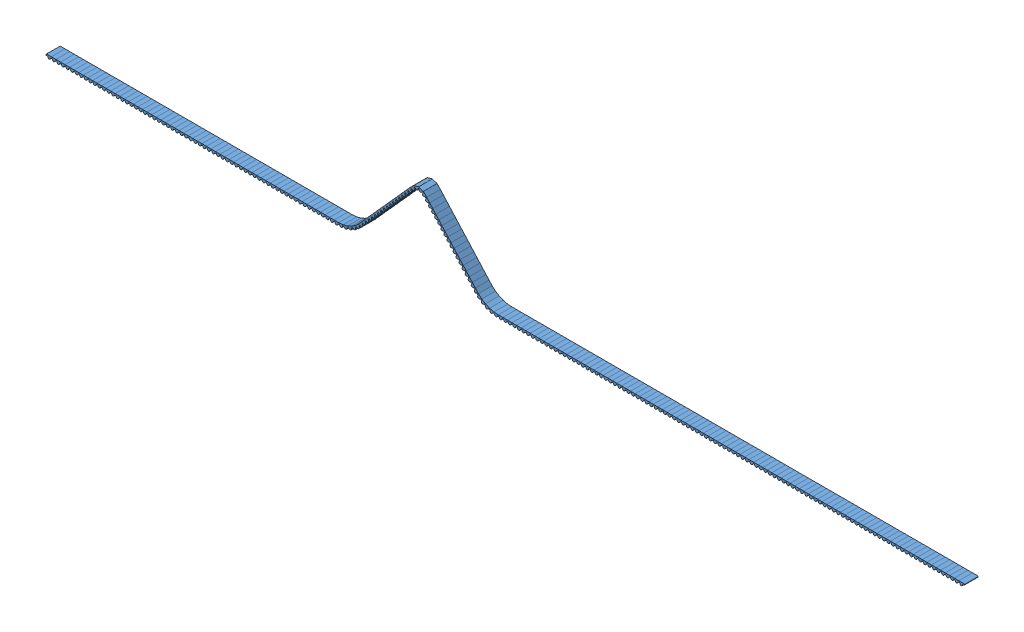
SolidWorks assembly TimingBelt2, configuration Timing Belt 430mm. Lengths in mm.
Overall size (824.67 32.64 6.23).
215 component instances, 2 part files, 2 mates.
Components (placement in the parent):
- Path^TimingBelt2-1: Path^TimingBelt2 [По умолчанию] at (723.3973 0 0) size (824.67 31.3 0) (virtual)
- PartOfBeltP2W6^TimingBelt2-1: PartOfBeltP2W6^TimingBelt2 [По умолчанию] at (982.9414 0 6) x (-1 0 0) z (0 0 -1) size (2.75 1.38 6.23) (virtual)
- PartOfBeltP2W6^TimingBelt2-485: PartOfBeltP2W6^TimingBelt2 [По умолчанию] at (980.9414 0 6) x (-1 0 0) z (0 0 -1) size (2.75 1.38 6.23) (virtual)
- PartOfBeltP2W6^TimingBelt2-486: PartOfBeltP2W6^TimingBelt2 [По умолчанию] at (978.9414 0 6) x (-1 0 0) z (0 0 -1) size (2.75 1.38 6.23) (virtual)
- PartOfBeltP2W6^TimingBelt2-487: PartOfBeltP2W6^TimingBelt2 [По умолчанию] at (976.9414 0 6) x (-1 0 0) z (0 0 -1) size (2.75 1.38 6.23) (virtual)
- PartOfBeltP2W6^TimingBelt2-488: PartOfBeltP2W6^TimingBelt2 [По умолчанию] at (974.9414 0 6) x (-1 0 0) z (0 0 -1) size (2.75 1.38 6.23) (virtual)
- PartOfBeltP2W6^TimingBelt2-489: PartOfBeltP2W6^TimingBelt2 [По умолчанию] at (972.9414 0 6) x (-1 0 0) z (0 0 -1) size (2.75 1.38 6.23) (virtual)
- PartOfBeltP2W6^TimingBelt2-490: PartOfBeltP2W6^TimingBelt2 [По умолчанию] at (970.9414 0 6) x (-1 0 0) z (0 0 -1) size (2.75 1.38 6.23) (virtual)
- PartOfBeltP2W6^TimingBelt2-491: PartOfBeltP2W6^TimingBelt2 [По умолчанию] at (968.9414 0 6) x (-1 0 0) z (0 0 -1) size (2.75 1.38 6.23) (virtual)
- PartOfBeltP2W6^TimingBelt2-492: PartOfBeltP2W6^TimingBelt2 [По умолчанию] at (966.9414 0 6) x (-1 0 0) z (0 0 -1) size (2.75 1.38 6.23) (virtual)
- PartOfBeltP2W6^TimingBelt2-493: PartOfBeltP2W6^TimingBelt2 [По умолчанию] at (964.9414 0 6) x (-1 0 0) z (0 0 -1) size (2.75 1.38 6.23) (virtual)
- PartOfBeltP2W6^TimingBelt2-494: PartOfBeltP2W6^TimingBelt2 [По умолчанию] at (962.9414 0 6) x (-1 0 0) z (0 0 -1) size (2.75 1.38 6.23) (virtual)
- PartOfBeltP2W6^TimingBelt2-495: PartOfBeltP2W6^TimingBelt2 [По умолчанию] at (960.9414 0 6) x (-1 0 0) z (0 0 -1) size (2.75 1.38 6.23) (virtual)
- PartOfBeltP2W6^TimingBelt2-496: PartOfBeltP2W6^TimingBelt2 [По умолчанию] at (958.9414 0 6) x (-1 0 0) z (0 0 -1) size (2.75 1.38 6.23) (virtual)
- PartOfBeltP2W6^TimingBelt2-497: PartOfBeltP2W6^TimingBelt2 [По умолчанию] at (956.9414 0 6) x (-1 0 0) z (0 0 -1) size (2.75 1.38 6.23) (virtual)
- PartOfBeltP2W6^TimingBelt2-498: PartOfBeltP2W6^TimingBelt2 [По умолчанию] at (954.9414 0 6) x (-1 0 0) z (0 0 -1) size (2.75 1.38 6.23) (virtual)
- PartOfBeltP2W6^TimingBelt2-499: PartOfBeltP2W6^TimingBelt2 [По умолчанию] at (952.9414 0 6) x (-1 0 0) z (0 0 -1) size (2.75 1.38 6.23) (virtual)
- PartOfBeltP2W6^TimingBelt2-500: PartOfBeltP2W6^TimingBelt2 [По умолчанию] at (950.9414 0 6) x (-1 0 0) z (0 0 -1) size (2.75 1.38 6.23) (virtual)
- PartOfBeltP2W6^TimingBelt2-501: PartOfBeltP2W6^TimingBelt2 [По умолчанию] at (948.9414 0 6) x (-1 0 0) z (0 0 -1) size (2.75 1.38 6.23) (virtual)
- PartOfBeltP2W6^TimingBelt2-502: PartOfBeltP2W6^TimingBelt2 [По умолчанию] at (946.9414 0 6) x (-1 0 0) z (0 0 -1) size (2.75 1.38 6.23) (virtual)
- PartOfBeltP2W6^TimingBelt2-503: PartOfBeltP2W6^TimingBelt2 [По умолчанию] at (944.9414 0 6) x (-1 0 0) z (0 0 -1) size (2.75 1.38 6.23) (virtual)
- PartOfBeltP2W6^TimingBelt2-504: PartOfBeltP2W6^TimingBelt2 [По умолчанию] at (942.9414 0 6) x (-1 0 0) z (0 0 -1) size (2.75 1.38 6.23) (virtual)
- PartOfBeltP2W6^TimingBelt2-505: PartOfBeltP2W6^TimingBelt2 [По умолчанию] at (940.9414 0 6) x (-1 0 0) z (0 0 -1) size (2.75 1.38 6.23) (virtual)
- PartOfBeltP2W6^TimingBelt2-506: PartOfBeltP2W6^TimingBelt2 [По умолчанию] at (938.9414 0 6) x (-1 0 0) z (0 0 -1) size (2.75 1.38 6.23) (virtual)
- PartOfBeltP2W6^TimingBelt2-507: PartOfBeltP2W6^TimingBelt2 [По умолчанию] at (936.9414 0 6) x (-1 0 0) z (0 0 -1) size (2.75 1.38 6.23) (virtual)
- PartOfBeltP2W6^TimingBelt2-508: PartOfBeltP2W6^TimingBelt2 [По умолчанию] at (934.9414 0 6) x (-1 0 0) z (0 0 -1) size (2.75 1.38 6.23) (virtual)
- PartOfBeltP2W6^TimingBelt2-509: PartOfBeltP2W6^TimingBelt2 [По умолчанию] at (932.9414 0 6) x (-1 0 0) z (0 0 -1) size (2.75 1.38 6.23) (virtual)
- PartOfBeltP2W6^TimingBelt2-510: PartOfBeltP2W6^TimingBelt2 [По умолчанию] at (930.9414 0 6) x (-1 0 0) z (0 0 -1) size (2.75 1.38 6.23) (virtual)
- PartOfBeltP2W6^TimingBelt2-511: PartOfBeltP2W6^TimingBelt2 [По умолчанию] at (928.9414 0 6) x (-1 0 0) z (0 0 -1) size (2.75 1.38 6.23) (virtual)
- PartOfBeltP2W6^TimingBelt2-512: PartOfBeltP2W6^TimingBelt2 [По умолчанию] at (926.9414 0 6) x (-1 0 0) z (0 0 -1) size (2.75 1.38 6.23) (virtual)
- PartOfBeltP2W6^TimingBelt2-513: PartOfBeltP2W6^TimingBelt2 [По умолчанию] at (924.9414 0 6) x (-1 0 0) z (0 0 -1) size (2.75 1.38 6.23) (virtual)
- PartOfBeltP2W6^TimingBelt2-514: PartOfBeltP2W6^TimingBelt2 [По умолчанию] at (922.9414 0 6) x (-1 0 0) z (0 0 -1) size (2.75 1.38 6.23) (virtual)
- PartOfBeltP2W6^TimingBelt2-515: PartOfBeltP2W6^TimingBelt2 [По умолчанию] at (920.9414 0 6) x (-1 0 0) z (0 0 -1) size (2.75 1.38 6.23) (virtual)
- PartOfBeltP2W6^TimingBelt2-516: PartOfBeltP2W6^TimingBelt2 [По умолчанию] at (918.9414 0 6) x (-1 0 0) z (0 0 -1) size (2.75 1.38 6.23) (virtual)
- PartOfBeltP2W6^TimingBelt2-517: PartOfBeltP2W6^TimingBelt2 [По умолчанию] at (916.9414 0 6) x (-1 0 0) z (0 0 -1) size (2.75 1.38 6.23) (virtual)
- PartOfBeltP2W6^TimingBelt2-518: PartOfBeltP2W6^TimingBelt2 [По умолчанию] at (914.9414 0 6) x (-1 0 0) z (0 0 -1) size (2.75 1.38 6.23) (virtual)
- PartOfBeltP2W6^TimingBelt2-519: PartOfBeltP2W6^TimingBelt2 [По умолчанию] at (912.9414 0 6) x (-1 0 0) z (0 0 -1) size (2.75 1.38 6.23) (virtual)
- PartOfBeltP2W6^TimingBelt2-520: PartOfBeltP2W6^TimingBelt2 [По умолчанию] at (910.9414 0 6) x (-1 0 0) z (0 0 -1) size (2.75 1.38 6.23) (virtual)
- PartOfBeltP2W6^TimingBelt2-521: PartOfBeltP2W6^TimingBelt2 [По умолчанию] at (908.9414 0 6) x (-1 0 0) z (0 0 -1) size (2.75 1.38 6.23) (virtual)
- PartOfBeltP2W6^TimingBelt2-522: PartOfBeltP2W6^TimingBelt2 [По умолчанию] at (906.9414 0 6) x (-1 0 0) z (0 0 -1) size (2.75 1.38 6.23) (virtual)
- PartOfBeltP2W6^TimingBelt2-523: PartOfBeltP2W6^TimingBelt2 [По умолчанию] at (904.9414 0 6) x (-1 0 0) z (0 0 -1) size (2.75 1.38 6.23) (virtual)
- PartOfBeltP2W6^TimingBelt2-524: PartOfBeltP2W6^TimingBelt2 [По умолчанию] at (902.9414 0 6) x (-1 0 0) z (0 0 -1) size (2.75 1.38 6.23) (virtual)
- PartOfBeltP2W6^TimingBelt2-525: PartOfBeltP2W6^TimingBelt2 [По умолчанию] at (900.9414 0 6) x (-1 0 0) z (0 0 -1) size (2.75 1.38 6.23) (virtual)
- PartOfBeltP2W6^TimingBelt2-526: PartOfBeltP2W6^TimingBelt2 [По умолчанию] at (898.9414 0 6) x (-1 0 0) z (0 0 -1) size (2.75 1.38 6.23) (virtual)
- PartOfBeltP2W6^TimingBelt2-527: PartOfBeltP2W6^TimingBelt2 [По умолчанию] at (896.9414 0 6) x (-1 0 0) z (0 0 -1) size (2.75 1.38 6.23) (virtual)
- PartOfBeltP2W6^TimingBelt2-528: PartOfBeltP2W6^TimingBelt2 [По умолчанию] at (894.9414 0 6) x (-1 0 0) z (0 0 -1) size (2.75 1.38 6.23) (virtual)
- PartOfBeltP2W6^TimingBelt2-529: PartOfBeltP2W6^TimingBelt2 [По умолчанию] at (892.9414 0 6) x (-1 0 0) z (0 0 -1) size (2.75 1.38 6.23) (virtual)
- PartOfBeltP2W6^TimingBelt2-530: PartOfBeltP2W6^TimingBelt2 [По умолчанию] at (890.9414 0 6) x (-1 0 0) z (0 0 -1) size (2.75 1.38 6.23) (virtual)
- PartOfBeltP2W6^TimingBelt2-531: PartOfBeltP2W6^TimingBelt2 [По умолчанию] at (888.9414 0 6) x (-1 0 0) z (0 0 -1) size (2.75 1.38 6.23) (virtual)
- PartOfBeltP2W6^TimingBelt2-532: PartOfBeltP2W6^TimingBelt2 [По умолчанию] at (886.9414 0 6) x (-1 0 0) z (0 0 -1) size (2.75 1.38 6.23) (virtual)
- PartOfBeltP2W6^TimingBelt2-533: PartOfBeltP2W6^TimingBelt2 [По умолчанию] at (884.9414 0 6) x (-1 0 0) z (0 0 -1) size (2.75 1.38 6.23) (virtual)
- PartOfBeltP2W6^TimingBelt2-534: PartOfBeltP2W6^TimingBelt2 [По умолчанию] at (882.9414 0 6) x (-1 0 0) z (0 0 -1) size (2.75 1.38 6.23) (virtual)
- PartOfBeltP2W6^TimingBelt2-535: PartOfBeltP2W6^TimingBelt2 [По умолчанию] at (880.9414 0 6) x (-1 0 0) z (0 0 -1) size (2.75 1.38 6.23) (virtual)
- PartOfBeltP2W6^TimingBelt2-536: PartOfBeltP2W6^TimingBelt2 [По умолчанию] at (878.9414 0 6) x (-1 0 0) z (0 0 -1) size (2.75 1.38 6.23) (virtual)
- PartOfBeltP2W6^TimingBelt2-537: PartOfBeltP2W6^TimingBelt2 [По умолчанию] at (876.9414 0 6) x (-1 0 0) z (0 0 -1) size (2.75 1.38 6.23) (virtual)
- PartOfBeltP2W6^TimingBelt2-538: PartOfBeltP2W6^TimingBelt2 [По умолчанию] at (874.9414 0 6) x (-1 0 0) z (0 0 -1) size (2.75 1.38 6.23) (virtual)
- PartOfBeltP2W6^TimingBelt2-539: PartOfBeltP2W6^TimingBelt2 [По умолчанию] at (872.9414 0 6) x (-1 0 0) z (0 0 -1) size (2.75 1.38 6.23) (virtual)
- PartOfBeltP2W6^TimingBelt2-540: PartOfBeltP2W6^TimingBelt2 [По умолчанию] at (870.9414 0 6) x (-1 0 0) z (0 0 -1) size (2.75 1.38 6.23) (virtual)
- PartOfBeltP2W6^TimingBelt2-541: PartOfBeltP2W6^TimingBelt2 [По умолчанию] at (868.9414 0 6) x (-1 0 0) z (0 0 -1) size (2.75 1.38 6.23) (virtual)
- PartOfBeltP2W6^TimingBelt2-542: PartOfBeltP2W6^TimingBelt2 [По умолчанию] at (866.9414 0 6) x (-1 0 0) z (0 0 -1) size (2.75 1.38 6.23) (virtual)
- PartOfBeltP2W6^TimingBelt2-543: PartOfBeltP2W6^TimingBelt2 [По умолчанию] at (864.9414 0 6) x (-1 0 0) z (0 0 -1) size (2.75 1.38 6.23) (virtual)
- PartOfBeltP2W6^TimingBelt2-544: PartOfBeltP2W6^TimingBelt2 [По умолчанию] at (862.9414 0 6) x (-1 0 0) z (0 0 -1) size (2.75 1.38 6.23) (virtual)
- PartOfBeltP2W6^TimingBelt2-545: PartOfBeltP2W6^TimingBelt2 [По умолчанию] at (860.9414 0 6) x (-1 0 0) z (0 0 -1) size (2.75 1.38 6.23) (virtual)
- PartOfBeltP2W6^TimingBelt2-546: PartOfBeltP2W6^TimingBelt2 [По умолчанию] at (858.9414 0 6) x (-1 0 0) z (0 0 -1) size (2.75 1.38 6.23) (virtual)
- PartOfBeltP2W6^TimingBelt2-547: PartOfBeltP2W6^TimingBelt2 [По умолчанию] at (856.9414 0 6) x (-1 0 0) z (0 0 -1) size (2.75 1.38 6.23) (virtual)
- PartOfBeltP2W6^TimingBelt2-548: PartOfBeltP2W6^TimingBelt2 [По умолчанию] at (854.9414 0 6) x (-1 0 0) z (0 0 -1) size (2.75 1.38 6.23) (virtual)
- PartOfBeltP2W6^TimingBelt2-549: PartOfBeltP2W6^TimingBelt2 [По умолчанию] at (852.9414 0 6) x (-1 0 0) z (0 0 -1) size (2.75 1.38 6.23) (virtual)
- PartOfBeltP2W6^TimingBelt2-550: PartOfBeltP2W6^TimingBelt2 [По умолчанию] at (850.9414 0 6) x (-1 0 0) z (0 0 -1) size (2.75 1.38 6.23) (virtual)
- PartOfBeltP2W6^TimingBelt2-551: PartOfBeltP2W6^TimingBelt2 [По умолчанию] at (848.9414 0 6) x (-1 0 0) z (0 0 -1) size (2.75 1.38 6.23) (virtual)
- PartOfBeltP2W6^TimingBelt2-552: PartOfBeltP2W6^TimingBelt2 [По умолчанию] at (846.9414 0 6) x (-1 0 0) z (0 0 -1) size (2.75 1.38 6.23) (virtual)
- PartOfBeltP2W6^TimingBelt2-553: PartOfBeltP2W6^TimingBelt2 [По умолчанию] at (844.9414 0 6) x (-1 0 0) z (0 0 -1) size (2.75 1.38 6.23) (virtual)
- PartOfBeltP2W6^TimingBelt2-554: PartOfBeltP2W6^TimingBelt2 [По умолчанию] at (842.9414 0 6) x (-1 0 0) z (0 0 -1) size (2.75 1.38 6.23) (virtual)
- PartOfBeltP2W6^TimingBelt2-555: PartOfBeltP2W6^TimingBelt2 [По умолчанию] at (840.9414 0 6) x (-1 0 0) z (0 0 -1) size (2.75 1.38 6.23) (virtual)
- PartOfBeltP2W6^TimingBelt2-556: PartOfBeltP2W6^TimingBelt2 [По умолчанию] at (838.9414 0 6) x (-1 0 0) z (0 0 -1) size (2.75 1.38 6.23) (virtual)
- PartOfBeltP2W6^TimingBelt2-557: PartOfBeltP2W6^TimingBelt2 [По умолчанию] at (836.9414 0 6) x (-1 0 0) z (0 0 -1) size (2.75 1.38 6.23) (virtual)
- PartOfBeltP2W6^TimingBelt2-558: PartOfBeltP2W6^TimingBelt2 [По умолчанию] at (834.9414 0 6) x (-1 0 0) z (0 0 -1) size (2.75 1.38 6.23) (virtual)
- PartOfBeltP2W6^TimingBelt2-559: PartOfBeltP2W6^TimingBelt2 [По умолчанию] at (832.9414 0 6) x (-1 0 0) z (0 0 -1) size (2.75 1.38 6.23) (virtual)
- PartOfBeltP2W6^TimingBelt2-560: PartOfBeltP2W6^TimingBelt2 [По умолчанию] at (830.9414 0 6) x (-1 0 0) z (0 0 -1) size (2.75 1.38 6.23) (virtual)
- PartOfBeltP2W6^TimingBelt2-561: PartOfBeltP2W6^TimingBelt2 [По умолчанию] at (828.9414 0 6) x (-1 0 0) z (0 0 -1) size (2.75 1.38 6.23) (virtual)
- PartOfBeltP2W6^TimingBelt2-562: PartOfBeltP2W6^TimingBelt2 [По умолчанию] at (826.9414 0 6) x (-1 0 0) z (0 0 -1) size (2.75 1.38 6.23) (virtual)
- PartOfBeltP2W6^TimingBelt2-563: PartOfBeltP2W6^TimingBelt2 [По умолчанию] at (824.9414 0 6) x (-1 0 0) z (0 0 -1) size (2.75 1.38 6.23) (virtual)
- PartOfBeltP2W6^TimingBelt2-564: PartOfBeltP2W6^TimingBelt2 [По умолчанию] at (822.9414 0 6) x (-1 0 0) z (0 0 -1) size (2.75 1.38 6.23) (virtual)
- PartOfBeltP2W6^TimingBelt2-565: PartOfBeltP2W6^TimingBelt2 [По умолчанию] at (820.9414 0 6) x (-1 0 0) z (0 0 -1) size (2.75 1.38 6.23) (virtual)
- PartOfBeltP2W6^TimingBelt2-566: PartOfBeltP2W6^TimingBelt2 [По умолчанию] at (818.9414 0 6) x (-1 0 0) z (0 0 -1) size (2.75 1.38 6.23) (virtual)
- PartOfBeltP2W6^TimingBelt2-567: PartOfBeltP2W6^TimingBelt2 [По умолчанию] at (816.9414 0 6) x (-1 0 0) z (0 0 -1) size (2.75 1.38 6.23) (virtual)
- PartOfBeltP2W6^TimingBelt2-568: PartOfBeltP2W6^TimingBelt2 [По умолчанию] at (814.9414 0 6) x (-1 0 0) z (0 0 -1) size (2.75 1.38 6.23) (virtual)
- PartOfBeltP2W6^TimingBelt2-569: PartOfBeltP2W6^TimingBelt2 [По умолчанию] at (812.9414 0 6) x (-1 0 0) z (0 0 -1) size (2.75 1.38 6.23) (virtual)
- PartOfBeltP2W6^TimingBelt2-570: PartOfBeltP2W6^TimingBelt2 [По умолчанию] at (810.9414 0 6) x (-1 0 0) z (0 0 -1) size (2.75 1.38 6.23) (virtual)
- PartOfBeltP2W6^TimingBelt2-571: PartOfBeltP2W6^TimingBelt2 [По умолчанию] at (808.9414 0 6) x (-1 0 0) z (0 0 -1) size (2.75 1.38 6.23) (virtual)
- PartOfBeltP2W6^TimingBelt2-572: PartOfBeltP2W6^TimingBelt2 [По умолчанию] at (806.9414 0 6) x (-1 0 0) z (0 0 -1) size (2.75 1.38 6.23) (virtual)
- PartOfBeltP2W6^TimingBelt2-573: PartOfBeltP2W6^TimingBelt2 [По умолчанию] at (804.9414 0 6) x (-1 0 0) z (0 0 -1) size (2.75 1.38 6.23) (virtual)
- PartOfBeltP2W6^TimingBelt2-574: PartOfBeltP2W6^TimingBelt2 [По умолчанию] at (802.9414 0 6) x (-1 0 0) z (0 0 -1) size (2.75 1.38 6.23) (virtual)
- PartOfBeltP2W6^TimingBelt2-575: PartOfBeltP2W6^TimingBelt2 [По умолчанию] at (800.9414 0 6) x (-1 0 0) z (0 0 -1) size (2.75 1.38 6.23) (virtual)
- PartOfBeltP2W6^TimingBelt2-576: PartOfBeltP2W6^TimingBelt2 [По умолчанию] at (798.9414 0 6) x (-1 0 0) z (0 0 -1) size (2.75 1.38 6.23) (virtual)
- PartOfBeltP2W6^TimingBelt2-577: PartOfBeltP2W6^TimingBelt2 [По умолчанию] at (796.9414 0 6) x (-1 0 0) z (0 0 -1) size (2.75 1.38 6.23) (virtual)
- PartOfBeltP2W6^TimingBelt2-578: PartOfBeltP2W6^TimingBelt2 [По умолчанию] at (794.9414 0 6) x (-1 0 0) z (0 0 -1) size (2.75 1.38 6.23) (virtual)
- PartOfBeltP2W6^TimingBelt2-579: PartOfBeltP2W6^TimingBelt2 [По умолчанию] at (792.9414 0 6) x (-1 0 0) z (0 0 -1) size (2.75 1.38 6.23) (virtual)
- PartOfBeltP2W6^TimingBelt2-580: PartOfBeltP2W6^TimingBelt2 [По умолчанию] at (790.9414 0 6) x (-1 0 0) z (0 0 -1) size (2.75 1.38 6.23) (virtual)
- PartOfBeltP2W6^TimingBelt2-581: PartOfBeltP2W6^TimingBelt2 [По умолчанию] at (788.9414 0 6) x (-1 0 0) z (0 0 -1) size (2.75 1.38 6.23) (virtual)
- PartOfBeltP2W6^TimingBelt2-582: PartOfBeltP2W6^TimingBelt2 [По умолчанию] at (786.9414 0 6) x (-1 0 0) z (0 0 -1) size (2.75 1.38 6.23) (virtual)
- PartOfBeltP2W6^TimingBelt2-583: PartOfBeltP2W6^TimingBelt2 [По умолчанию] at (784.9414 0 6) x (-1 0 0) z (0 0 -1) size (2.75 1.38 6.23) (virtual)
- PartOfBeltP2W6^TimingBelt2-584: PartOfBeltP2W6^TimingBelt2 [По умолчанию] at (782.9414 0 6) x (-1 0 0) z (0 0 -1) size (2.75 1.38 6.23) (virtual)
- PartOfBeltP2W6^TimingBelt2-585: PartOfBeltP2W6^TimingBelt2 [По умолчанию] at (780.9414 0 6) x (-1 0 0) z (0 0 -1) size (2.75 1.38 6.23) (virtual)
- PartOfBeltP2W6^TimingBelt2-586: PartOfBeltP2W6^TimingBelt2 [По умолчанию] at (778.9441 0.0737 6) x (-0.99728 0.073711 0) z (0 0 -1) size (2.75 1.38 6.23) (virtual)
- PartOfBeltP2W6^TimingBelt2-587: PartOfBeltP2W6^TimingBelt2 [По умолчанию] at (776.9746 0.3812 6) x (-0.97228 0.233821 0) z (0 0 -1) size (2.75 1.38 6.23) (virtual)
- PartOfBeltP2W6^TimingBelt2-588: PartOfBeltP2W6^TimingBelt2 [По умолчанию] at (775.0806 1.003 6) x (-0.921691 0.387925 0) z (0 0 -1) size (2.75 1.38 6.23) (virtual)
- PartOfBeltP2W6^TimingBelt2-589: PartOfBeltP2W6^TimingBelt2 [По умолчанию] at (773.312 1.9227 6) x (-0.846849 0.531833 0) z (0 0 -1) size (2.75 1.38 6.23) (virtual)
- PartOfBeltP2W6^TimingBelt2-590: PartOfBeltP2W6^TimingBelt2 [По умолчанию] at (771.714 3.1146 6) x (-0.751241 0.660028 0) z (0 0 -1) size (2.75 1.38 6.23) (virtual)
- PartOfBeltP2W6^TimingBelt2-591: PartOfBeltP2W6^TimingBelt2 [По умолчанию] at (770.2934 4.5176 6) x (-0.669304 0.742989 0) z (0 0 -1) size (2.75 1.38 6.23) (virtual)
- PartOfBeltP2W6^TimingBelt2-592: PartOfBeltP2W6^TimingBelt2 [По умолчанию] at (768.9559 6.0045 6) x (-0.668253 0.743934 0) z (0 0 -1) size (2.75 1.38 6.23) (virtual)
- PartOfBeltP2W6^TimingBelt2-593: PartOfBeltP2W6^TimingBelt2 [По умолчанию] at (767.6193 7.4924 6) x (-0.668253 0.743934 0) z (0 0 -1) size (2.75 1.38 6.23) (virtual)
- PartOfBeltP2W6^TimingBelt2-594: PartOfBeltP2W6^TimingBelt2 [По умолчанию] at (766.2828 8.9803 6) x (-0.668253 0.743934 0) z (0 0 -1) size (2.75 1.38 6.23) (virtual)
- PartOfBeltP2W6^TimingBelt2-595: PartOfBeltP2W6^TimingBelt2 [По умолчанию] at (764.9463 10.4682 6) x (-0.668253 0.743934 0) z (0 0 -1) size (2.75 1.38 6.23) (virtual)
- PartOfBeltP2W6^TimingBelt2-596: PartOfBeltP2W6^TimingBelt2 [По умолчанию] at (763.6098 11.956 6) x (-0.668253 0.743934 0) z (0 0 -1) size (2.75 1.38 6.23) (virtual)
- PartOfBeltP2W6^TimingBelt2-597: PartOfBeltP2W6^TimingBelt2 [По умолчанию] at (762.2733 13.4439 6) x (-0.668253 0.743934 0) z (0 0 -1) size (2.75 1.38 6.23) (virtual)
- PartOfBeltP2W6^TimingBelt2-598: PartOfBeltP2W6^TimingBelt2 [По умолчанию] at (760.9368 14.9318 6) x (-0.668253 0.743934 0) z (0 0 -1) size (2.75 1.38 6.23) (virtual)
- PartOfBeltP2W6^TimingBelt2-599: PartOfBeltP2W6^TimingBelt2 [По умолчанию] at (759.6003 16.4196 6) x (-0.668253 0.743934 0) z (0 0 -1) size (2.75 1.38 6.23) (virtual)
- PartOfBeltP2W6^TimingBelt2-600: PartOfBeltP2W6^TimingBelt2 [По умолчанию] at (758.2638 17.9075 6) x (-0.668253 0.743934 0) z (0 0 -1) size (2.75 1.38 6.23) (virtual)
- PartOfBeltP2W6^TimingBelt2-601: PartOfBeltP2W6^TimingBelt2 [По умолчанию] at (756.9273 19.3954 6) x (-0.668253 0.743934 0) z (0 0 -1) size (2.75 1.38 6.23) (virtual)
- PartOfBeltP2W6^TimingBelt2-602: PartOfBeltP2W6^TimingBelt2 [По умолчанию] at (755.5908 20.8832 6) x (-0.668253 0.743934 0) z (0 0 -1) size (2.75 1.38 6.23) (virtual)
- PartOfBeltP2W6^TimingBelt2-603: PartOfBeltP2W6^TimingBelt2 [По умолчанию] at (754.2543 22.3711 6) x (-0.668253 0.743934 0) z (0 0 -1) size (2.75 1.38 6.23) (virtual)
- PartOfBeltP2W6^TimingBelt2-604: PartOfBeltP2W6^TimingBelt2 [По умолчанию] at (752.9178 23.859 6) x (-0.668253 0.743934 0) z (0 0 -1) size (2.75 1.38 6.23) (virtual)
- PartOfBeltP2W6^TimingBelt2-605: PartOfBeltP2W6^TimingBelt2 [По умолчанию] at (751.5813 25.3468 6) x (-0.668253 0.743934 0) z (0 0 -1) size (2.75 1.38 6.23) (virtual)
- PartOfBeltP2W6^TimingBelt2-606: PartOfBeltP2W6^TimingBelt2 [По умолчанию] at (750.2448 26.8347 6) x (-0.668253 0.743934 0) z (0 0 -1) size (2.75 1.38 6.23) (virtual)
- PartOfBeltP2W6^TimingBelt2-607: PartOfBeltP2W6^TimingBelt2 [По умолчанию] at (748.9083 28.3226 6) x (-0.668253 0.743934 0) z (0 0 -1) size (2.75 1.38 6.23) (virtual)
- PartOfBeltP2W6^TimingBelt2-608: PartOfBeltP2W6^TimingBelt2 [По умолчанию] at (747.541 29.7816 6) x (-0.699008 0.715114 0) z (0 0 -1) size (2.75 1.38 6.23) (virtual)
- PartOfBeltP2W6^TimingBelt2-609: PartOfBeltP2W6^TimingBelt2 [По умолчанию] at (745.8932 30.8127 6) x (-0.948772 0.315961 0) z (0 0 -1) size (2.75 1.38 6.23) (virtual)
- PartOfBeltP2W6^TimingBelt2-610: PartOfBeltP2W6^TimingBelt2 [По умолчанию] at (743.9796 30.8657 6) x (-0.96481 -0.262949 0) z (0 0 -1) size (2.75 1.38 6.23) (virtual)
- PartOfBeltP2W6^TimingBelt2-611: PartOfBeltP2W6^TimingBelt2 [По умолчанию] at (742.2985 29.905 6) x (-0.716294 -0.697798 0) z (0 0 -1) size (2.75 1.38 6.23) (virtual)
- PartOfBeltP2W6^TimingBelt2-612: PartOfBeltP2W6^TimingBelt2 [По умолчанию] at (740.914 28.4632 6) x (-0.668253 -0.743934 0) z (0 0 -1) size (2.75 1.38 6.23) (virtual)
- PartOfBeltP2W6^TimingBelt2-613: PartOfBeltP2W6^TimingBelt2 [По умолчанию] at (739.5775 26.9754 6) x (-0.668253 -0.743934 0) z (0 0 -1) size (2.75 1.38 6.23) (virtual)
- PartOfBeltP2W6^TimingBelt2-614: PartOfBeltP2W6^TimingBelt2 [По умолчанию] at (738.241 25.4875 6) x (-0.668253 -0.743934 0) z (0 0 -1) size (2.75 1.38 6.23) (virtual)
- PartOfBeltP2W6^TimingBelt2-615: PartOfBeltP2W6^TimingBelt2 [По умолчанию] at (736.9045 23.9996 6) x (-0.668253 -0.743934 0) z (0 0 -1) size (2.75 1.38 6.23) (virtual)
- PartOfBeltP2W6^TimingBelt2-616: PartOfBeltP2W6^TimingBelt2 [По умолчанию] at (735.568 22.5118 6) x (-0.668253 -0.743934 0) z (0 0 -1) size (2.75 1.38 6.23) (virtual)
- PartOfBeltP2W6^TimingBelt2-617: PartOfBeltP2W6^TimingBelt2 [По умолчанию] at (734.2314 21.0239 6) x (-0.668253 -0.743934 0) z (0 0 -1) size (2.75 1.38 6.23) (virtual)
- PartOfBeltP2W6^TimingBelt2-618: PartOfBeltP2W6^TimingBelt2 [По умолчанию] at (732.8949 19.536 6) x (-0.668253 -0.743934 0) z (0 0 -1) size (2.75 1.38 6.23) (virtual)
- PartOfBeltP2W6^TimingBelt2-619: PartOfBeltP2W6^TimingBelt2 [По умолчанию] at (731.5584 18.0481 6) x (-0.668253 -0.743934 0) z (0 0 -1) size (2.75 1.38 6.23) (virtual)
- PartOfBeltP2W6^TimingBelt2-620: PartOfBeltP2W6^TimingBelt2 [По умолчанию] at (730.2219 16.5603 6) x (-0.668253 -0.743934 0) z (0 0 -1) size (2.75 1.38 6.23) (virtual)
- PartOfBeltP2W6^TimingBelt2-621: PartOfBeltP2W6^TimingBelt2 [По умолчанию] at (728.8854 15.0724 6) x (-0.668253 -0.743934 0) z (0 0 -1) size (2.75 1.38 6.23) (virtual)
- PartOfBeltP2W6^TimingBelt2-622: PartOfBeltP2W6^TimingBelt2 [По умолчанию] at (727.5489 13.5845 6) x (-0.668253 -0.743934 0) z (0 0 -1) size (2.75 1.38 6.23) (virtual)
- PartOfBeltP2W6^TimingBelt2-623: PartOfBeltP2W6^TimingBelt2 [По умолчанию] at (726.2124 12.0967 6) x (-0.668253 -0.743934 0) z (0 0 -1) size (2.75 1.38 6.23) (virtual)
- PartOfBeltP2W6^TimingBelt2-624: PartOfBeltP2W6^TimingBelt2 [По умолчанию] at (724.8759 10.6088 6) x (-0.668253 -0.743934 0) z (0 0 -1) size (2.75 1.38 6.23) (virtual)
- PartOfBeltP2W6^TimingBelt2-625: PartOfBeltP2W6^TimingBelt2 [По умолчанию] at (723.5394 9.1209 6) x (-0.668253 -0.743934 0) z (0 0 -1) size (2.75 1.38 6.23) (virtual)
- PartOfBeltP2W6^TimingBelt2-626: PartOfBeltP2W6^TimingBelt2 [По умолчанию] at (722.2029 7.6331 6) x (-0.668253 -0.743934 0) z (0 0 -1) size (2.75 1.38 6.23) (virtual)
- PartOfBeltP2W6^TimingBelt2-627: PartOfBeltP2W6^TimingBelt2 [По умолчанию] at (720.8664 6.1452 6) x (-0.668253 -0.743934 0) z (0 0 -1) size (2.75 1.38 6.23) (virtual)
- PartOfBeltP2W6^TimingBelt2-628: PartOfBeltP2W6^TimingBelt2 [По умолчанию] at (719.5297 4.6575 6) x (-0.668435 -0.74377 0) z (0 0 -1) size (2.75 1.38 6.23) (virtual)
- PartOfBeltP2W6^TimingBelt2-629: PartOfBeltP2W6^TimingBelt2 [По умолчанию] at (718.1211 3.2413 6) x (-0.740116 -0.672479 0) z (0 0 -1) size (2.75 1.38 6.23) (virtual)
- PartOfBeltP2W6^TimingBelt2-630: PartOfBeltP2W6^TimingBelt2 [По умолчанию] at (716.5424 2.024 6) x (-0.838607 -0.544737 0) z (0 0 -1) size (2.75 1.38 6.23) (virtual)
- PartOfBeltP2W6^TimingBelt2-631: PartOfBeltP2W6^TimingBelt2 [По умолчанию] at (714.7882 1.0773 6) x (-0.915643 -0.401991 0) z (0 0 -1) size (2.75 1.38 6.23) (virtual)
- PartOfBeltP2W6^TimingBelt2-632: PartOfBeltP2W6^TimingBelt2 [По умолчанию] at (712.9039 0.4266 6) x (-0.968588 -0.248669 0) z (0 0 -1) size (2.75 1.38 6.23) (virtual)
- PartOfBeltP2W6^TimingBelt2-633: PartOfBeltP2W6^TimingBelt2 [По умолчанию] at (710.9393 0.089 6) x (-0.996034 -0.088973 0) z (0 0 -1) size (2.75 1.38 6.23) (virtual)
- PartOfBeltP2W6^TimingBelt2-634: PartOfBeltP2W6^TimingBelt2 [По умолчанию] at (708.9433 0 6) x (-1 -0.000016 0) z (0 0 -1) size (2.75 1.38 6.23) (virtual)
- PartOfBeltP2W6^TimingBelt2-635: PartOfBeltP2W6^TimingBelt2 [По умолчанию] at (706.9433 0 6) x (-1 0 0) z (0 0 -1) size (2.75 1.38 6.23) (virtual)
- PartOfBeltP2W6^TimingBelt2-636: PartOfBeltP2W6^TimingBelt2 [По умолчанию] at (704.9433 0 6) x (-1 0 0) z (0 0 -1) size (2.75 1.38 6.23) (virtual)
- PartOfBeltP2W6^TimingBelt2-637: PartOfBeltP2W6^TimingBelt2 [По умолчанию] at (702.9433 0 6) x (-1 0 0) z (0 0 -1) size (2.75 1.38 6.23) (virtual)
- PartOfBeltP2W6^TimingBelt2-638: PartOfBeltP2W6^TimingBelt2 [По умолчанию] at (700.9433 0 6) x (-1 0 0) z (0 0 -1) size (2.75 1.38 6.23) (virtual)
- PartOfBeltP2W6^TimingBelt2-639: PartOfBeltP2W6^TimingBelt2 [По умолчанию] at (698.9433 0 6) x (-1 0 0) z (0 0 -1) size (2.75 1.38 6.23) (virtual)
- PartOfBeltP2W6^TimingBelt2-640: PartOfBeltP2W6^TimingBelt2 [По умолчанию] at (696.9433 0 6) x (-1 0 0) z (0 0 -1) size (2.75 1.38 6.23) (virtual)
- PartOfBeltP2W6^TimingBelt2-641: PartOfBeltP2W6^TimingBelt2 [По умолчанию] at (694.9433 0 6) x (-1 0 0) z (0 0 -1) size (2.75 1.38 6.23) (virtual)
- PartOfBeltP2W6^TimingBelt2-642: PartOfBeltP2W6^TimingBelt2 [По умолчанию] at (692.9433 0 6) x (-1 0 0) z (0 0 -1) size (2.75 1.38 6.23) (virtual)
- PartOfBeltP2W6^TimingBelt2-643: PartOfBeltP2W6^TimingBelt2 [По умолчанию] at (690.9433 0 6) x (-1 0 0) z (0 0 -1) size (2.75 1.38 6.23) (virtual)
- PartOfBeltP2W6^TimingBelt2-644: PartOfBeltP2W6^TimingBelt2 [По умолчанию] at (688.9433 0 6) x (-1 0 0) z (0 0 -1) size (2.75 1.38 6.23) (virtual)
- PartOfBeltP2W6^TimingBelt2-645: PartOfBeltP2W6^TimingBelt2 [По умолчанию] at (686.9433 0 6) x (-1 0 0) z (0 0 -1) size (2.75 1.38 6.23) (virtual)
- PartOfBeltP2W6^TimingBelt2-646: PartOfBeltP2W6^TimingBelt2 [По умолчанию] at (684.9433 0 6) x (-1 0 0) z (0 0 -1) size (2.75 1.38 6.23) (virtual)
- PartOfBeltP2W6^TimingBelt2-647: PartOfBeltP2W6^TimingBelt2 [По умолчанию] at (682.9433 0 6) x (-1 0 0) z (0 0 -1) size (2.75 1.38 6.23) (virtual)
- PartOfBeltP2W6^TimingBelt2-648: PartOfBeltP2W6^TimingBelt2 [По умолчанию] at (680.9433 0 6) x (-1 0 0) z (0 0 -1) size (2.75 1.38 6.23) (virtual)
- PartOfBeltP2W6^TimingBelt2-649: PartOfBeltP2W6^TimingBelt2 [По умолчанию] at (678.9433 0 6) x (-1 0 0) z (0 0 -1) size (2.75 1.38 6.23) (virtual)
- PartOfBeltP2W6^TimingBelt2-650: PartOfBeltP2W6^TimingBelt2 [По умолчанию] at (676.9433 0 6) x (-1 0 0) z (0 0 -1) size (2.75 1.38 6.23) (virtual)
- PartOfBeltP2W6^TimingBelt2-651: PartOfBeltP2W6^TimingBelt2 [По умолчанию] at (674.9433 0 6) x (-1 0 0) z (0 0 -1) size (2.75 1.38 6.23) (virtual)
- PartOfBeltP2W6^TimingBelt2-652: PartOfBeltP2W6^TimingBelt2 [По умолчанию] at (672.9433 0 6) x (-1 0 0) z (0 0 -1) size (2.75 1.38 6.23) (virtual)
- PartOfBeltP2W6^TimingBelt2-653: PartOfBeltP2W6^TimingBelt2 [По умолчанию] at (670.9433 0 6) x (-1 0 0) z (0 0 -1) size (2.75 1.38 6.23) (virtual)
- PartOfBeltP2W6^TimingBelt2-654: PartOfBeltP2W6^TimingBelt2 [По умолчанию] at (668.9433 0 6) x (-1 0 0) z (0 0 -1) size (2.75 1.38 6.23) (virtual)
- PartOfBeltP2W6^TimingBelt2-655: PartOfBeltP2W6^TimingBelt2 [По умолчанию] at (666.9433 0 6) x (-1 0 0) z (0 0 -1) size (2.75 1.38 6.23) (virtual)
- PartOfBeltP2W6^TimingBelt2-656: PartOfBeltP2W6^TimingBelt2 [По умолчанию] at (664.9433 0 6) x (-1 0 0) z (0 0 -1) size (2.75 1.38 6.23) (virtual)
- PartOfBeltP2W6^TimingBelt2-657: PartOfBeltP2W6^TimingBelt2 [По умолчанию] at (662.9433 0 6) x (-1 0 0) z (0 0 -1) size (2.75 1.38 6.23) (virtual)
- PartOfBeltP2W6^TimingBelt2-658: PartOfBeltP2W6^TimingBelt2 [По умолчанию] at (660.9433 0 6) x (-1 0 0) z (0 0 -1) size (2.75 1.38 6.23) (virtual)
- PartOfBeltP2W6^TimingBelt2-659: PartOfBeltP2W6^TimingBelt2 [По умолчанию] at (658.9433 0 6) x (-1 0 0) z (0 0 -1) size (2.75 1.38 6.23) (virtual)
- PartOfBeltP2W6^TimingBelt2-660: PartOfBeltP2W6^TimingBelt2 [По умолчанию] at (656.9433 0 6) x (-1 0 0) z (0 0 -1) size (2.75 1.38 6.23) (virtual)
- PartOfBeltP2W6^TimingBelt2-661: PartOfBeltP2W6^TimingBelt2 [По умолчанию] at (654.9433 0 6) x (-1 0 0) z (0 0 -1) size (2.75 1.38 6.23) (virtual)
- PartOfBeltP2W6^TimingBelt2-662: PartOfBeltP2W6^TimingBelt2 [По умолчанию] at (652.9433 0 6) x (-1 0 0) z (0 0 -1) size (2.75 1.38 6.23) (virtual)
- PartOfBeltP2W6^TimingBelt2-663: PartOfBeltP2W6^TimingBelt2 [По умолчанию] at (650.9433 0 6) x (-1 0 0) z (0 0 -1) size (2.75 1.38 6.23) (virtual)
- PartOfBeltP2W6^TimingBelt2-664: PartOfBeltP2W6^TimingBelt2 [По умолчанию] at (648.9433 0 6) x (-1 0 0) z (0 0 -1) size (2.75 1.38 6.23) (virtual)
- PartOfBeltP2W6^TimingBelt2-665: PartOfBeltP2W6^TimingBelt2 [По умолчанию] at (646.9433 0 6) x (-1 0 0) z (0 0 -1) size (2.75 1.38 6.23) (virtual)
- PartOfBeltP2W6^TimingBelt2-666: PartOfBeltP2W6^TimingBelt2 [По умолчанию] at (644.9433 0 6) x (-1 0 0) z (0 0 -1) size (2.75 1.38 6.23) (virtual)
- PartOfBeltP2W6^TimingBelt2-667: PartOfBeltP2W6^TimingBelt2 [По умолчанию] at (642.9433 0 6) x (-1 0 0) z (0 0 -1) size (2.75 1.38 6.23) (virtual)
- PartOfBeltP2W6^TimingBelt2-668: PartOfBeltP2W6^TimingBelt2 [По умолчанию] at (640.9433 0 6) x (-1 0 0) z (0 0 -1) size (2.75 1.38 6.23) (virtual)
- PartOfBeltP2W6^TimingBelt2-669: PartOfBeltP2W6^TimingBelt2 [По умолчанию] at (638.9433 0 6) x (-1 0 0) z (0 0 -1) size (2.75 1.38 6.23) (virtual)
- PartOfBeltP2W6^TimingBelt2-670: PartOfBeltP2W6^TimingBelt2 [По умолчанию] at (636.9433 0 6) x (-1 0 0) z (0 0 -1) size (2.75 1.38 6.23) (virtual)
- PartOfBeltP2W6^TimingBelt2-671: PartOfBeltP2W6^TimingBelt2 [По умолчанию] at (634.9433 0 6) x (-1 0 0) z (0 0 -1) size (2.75 1.38 6.23) (virtual)
- PartOfBeltP2W6^TimingBelt2-672: PartOfBeltP2W6^TimingBelt2 [По умолчанию] at (632.9433 0 6) x (-1 0 0) z (0 0 -1) size (2.75 1.38 6.23) (virtual)
- PartOfBeltP2W6^TimingBelt2-673: PartOfBeltP2W6^TimingBelt2 [По умолчанию] at (630.9433 0 6) x (-1 0 0) z (0 0 -1) size (2.75 1.38 6.23) (virtual)
- PartOfBeltP2W6^TimingBelt2-674: PartOfBeltP2W6^TimingBelt2 [По умолчанию] at (628.9433 0 6) x (-1 0 0) z (0 0 -1) size (2.75 1.38 6.23) (virtual)
- PartOfBeltP2W6^TimingBelt2-675: PartOfBeltP2W6^TimingBelt2 [По умолчанию] at (626.9433 0 6) x (-1 0 0) z (0 0 -1) size (2.75 1.38 6.23) (virtual)
- PartOfBeltP2W6^TimingBelt2-676: PartOfBeltP2W6^TimingBelt2 [По умолчанию] at (624.9433 0 6) x (-1 0 0) z (0 0 -1) size (2.75 1.38 6.23) (virtual)
- PartOfBeltP2W6^TimingBelt2-677: PartOfBeltP2W6^TimingBelt2 [По умолчанию] at (622.9433 0 6) x (-1 0 0) z (0 0 -1) size (2.75 1.38 6.23) (virtual)
- PartOfBeltP2W6^TimingBelt2-678: PartOfBeltP2W6^TimingBelt2 [По умолчанию] at (620.9433 0 6) x (-1 0 0) z (0 0 -1) size (2.75 1.38 6.23) (virtual)
- PartOfBeltP2W6^TimingBelt2-679: PartOfBeltP2W6^TimingBelt2 [По умолчанию] at (618.9433 0 6) x (-1 0 0) z (0 0 -1) size (2.75 1.38 6.23) (virtual)
- PartOfBeltP2W6^TimingBelt2-680: PartOfBeltP2W6^TimingBelt2 [По умолчанию] at (616.9433 0 6) x (-1 0 0) z (0 0 -1) size (2.75 1.38 6.23) (virtual)
- PartOfBeltP2W6^TimingBelt2-681: PartOfBeltP2W6^TimingBelt2 [По умолчанию] at (614.9433 0 6) x (-1 0 0) z (0 0 -1) size (2.75 1.38 6.23) (virtual)
- PartOfBeltP2W6^TimingBelt2-682: PartOfBeltP2W6^TimingBelt2 [По умолчанию] at (612.9433 0 6) x (-1 0 0) z (0 0 -1) size (2.75 1.38 6.23) (virtual)
- PartOfBeltP2W6^TimingBelt2-683: PartOfBeltP2W6^TimingBelt2 [По умолчанию] at (610.9433 0 6) x (-1 0 0) z (0 0 -1) size (2.75 1.38 6.23) (virtual)
- PartOfBeltP2W6^TimingBelt2-684: PartOfBeltP2W6^TimingBelt2 [По умолчанию] at (608.9433 0 6) x (-1 0 0) z (0 0 -1) size (2.75 1.38 6.23) (virtual)
- PartOfBeltP2W6^TimingBelt2-685: PartOfBeltP2W6^TimingBelt2 [По умолчанию] at (606.9433 0 6) x (-1 0 0) z (0 0 -1) size (2.75 1.38 6.23) (virtual)
- PartOfBeltP2W6^TimingBelt2-686: PartOfBeltP2W6^TimingBelt2 [По умолчанию] at (604.9433 0 6) x (-1 0 0) z (0 0 -1) size (2.75 1.38 6.23) (virtual)
- PartOfBeltP2W6^TimingBelt2-687: PartOfBeltP2W6^TimingBelt2 [По умолчанию] at (602.9433 0 6) x (-1 0 0) z (0 0 -1) size (2.75 1.38 6.23) (virtual)
- PartOfBeltP2W6^TimingBelt2-688: PartOfBeltP2W6^TimingBelt2 [По умолчанию] at (600.9433 0 6) x (-1 0 0) z (0 0 -1) size (2.75 1.38 6.23) (virtual)
- PartOfBeltP2W6^TimingBelt2-689: PartOfBeltP2W6^TimingBelt2 [По умолчанию] at (598.9433 0 6) x (-1 0 0) z (0 0 -1) size (2.75 1.38 6.23) (virtual)
- PartOfBeltP2W6^TimingBelt2-690: PartOfBeltP2W6^TimingBelt2 [По умолчанию] at (596.9433 0 6) x (-1 0 0) z (0 0 -1) size (2.75 1.38 6.23) (virtual)
- PartOfBeltP2W6^TimingBelt2-691: PartOfBeltP2W6^TimingBelt2 [По умолчанию] at (594.9433 0 6) x (-1 0 0) z (0 0 -1) size (2.75 1.38 6.23) (virtual)
- PartOfBeltP2W6^TimingBelt2-692: PartOfBeltP2W6^TimingBelt2 [По умолчанию] at (592.9433 0 6) x (-1 0 0) z (0 0 -1) size (2.75 1.38 6.23) (virtual)
- PartOfBeltP2W6^TimingBelt2-693: PartOfBeltP2W6^TimingBelt2 [По умолчанию] at (590.9433 0 6) x (-1 0 0) z (0 0 -1) size (2.75 1.38 6.23) (virtual)
- PartOfBeltP2W6^TimingBelt2-694: PartOfBeltP2W6^TimingBelt2 [По умолчанию] at (588.9433 0 6) x (-1 0 0) z (0 0 -1) size (2.75 1.38 6.23) (virtual)
- PartOfBeltP2W6^TimingBelt2-695: PartOfBeltP2W6^TimingBelt2 [По умолчанию] at (586.9433 0 6) x (-1 0 0) z (0 0 -1) size (2.75 1.38 6.23) (virtual)
- PartOfBeltP2W6^TimingBelt2-696: PartOfBeltP2W6^TimingBelt2 [По умолчанию] at (584.9433 0 6) x (-1 0 0) z (0 0 -1) size (2.75 1.38 6.23) (virtual)
- PartOfBeltP2W6^TimingBelt2-697: PartOfBeltP2W6^TimingBelt2 [По умолчанию] at (582.9433 0 6) x (-1 0 0) z (0 0 -1) size (2.75 1.38 6.23) (virtual)
Mates (geometry in assembly coordinates):
- Coincident1: coincident aligned: plane of Path^TimingBelt2-1 through (723.3973 0 0) normal (0 0 1); plane of assembly through (0 0 0) normal (0 0 1)
- Coincident2: coincident aligned: plane of Path^TimingBelt2-1 through (723.3973 0 0) normal (0 1 0); plane of assembly through (0 0 0) normal (0 1 0)
